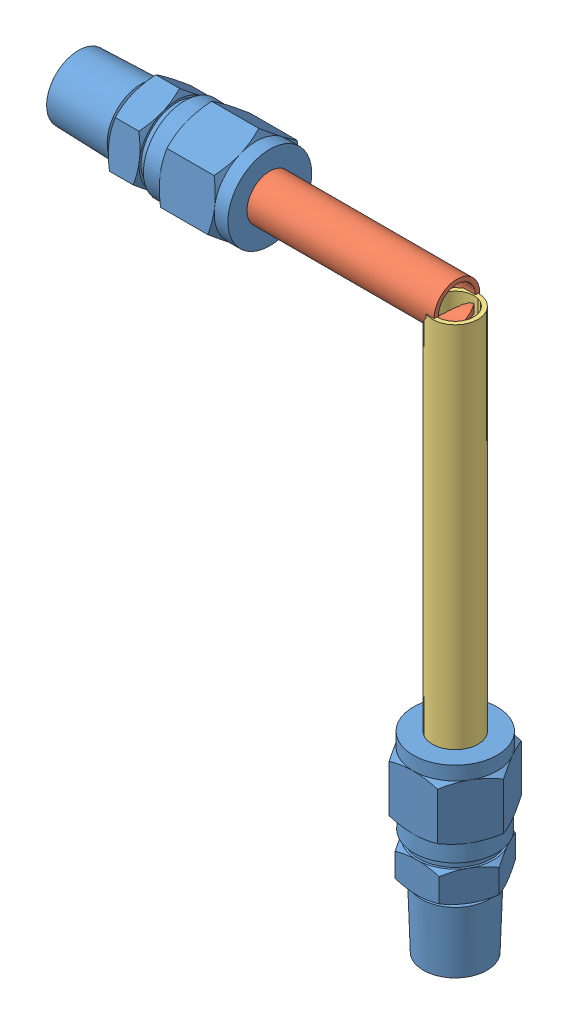
SolidWorks assembly Tube_5-regen additive coax swirl engine 3, configuration Default. Lengths in mm.
Overall size (88.9 128.46 25.3).
4 component instances, 3 part files, 4 mates.
Components (placement in the parent):
- straight fitting-1: straight fitting [.38 TUBE X .25 NPT] at (45.9715 41.275 0) x (-1 0 0) z (0 0.924225 0.381849) size (39.88 20.16 17.46)
- straight fitting-2: straight fitting [.38 TUBE X .25 NPT] at (124.7906 -75.2671 0.2978) x (0 -1 0) z (0 0 1) size (39.88 20.16 17.46)
- Tube-375X035^Tube_5-regen additive coax swirl engine 3-1: Tube-375X035^Tube_5-regen additive coax swirl engine 3 [Tube .375in OD X .035in Wall] at (69.0855 41.275 0) x (0 0.707107 0.707107) z (1 0 0) size (9.53 9.53 55.74) (virtual)
- Tube-375X035_1^Tube_5-regen additive coax swirl engine 3-1: Tube-375X035_1^Tube_5-regen additive coax swirl engine 3 [Tube .375in OD X .035in Wall] at (124.7906 -52.1531 0.2978) x (0.707107 0 0.707107) z (0 1 0) size (9.53 9.53 93.43) (virtual)
Mates (geometry in assembly coordinates):
- Concentric141: concentric: cylinder of addative coax swirl injector7-1 through (63.4136 41.275 0) axis (1 0 0) radius 5.5626; cylinder of straight fitting-1 through (83.0047 41.275 0) axis (-1 0 0) radius 4.5085
- Coincident111: coincident: plane of addative coax swirl injector7-1 through (53.5076 46.8376 0) normal (1 0 0); plane of straight fitting-1 through (53.5076 43.0936 -4.4016) normal (-1 0 0)
- Concentric1421: concentric: cylinder of straight fitting-2 through (124.7906 -38.2339 0.2978) axis (0 -1 0) radius 4.5085; cylinder of orifice_flow_meter-1/orifice_flow_meter_flange-1 through (124.7906 -57.8249 0.2978) axis (0 1 0) radius 5.5626
- Coincident1121: coincident: plane of straight fitting-2 through (120.0281 -67.7309 0.2978) normal (0 -1 0); plane of orifice_flow_meter-1/orifice_flow_meter_flange-1 through (122.0093 -67.7309 -4.5196) normal (0 1 0)
